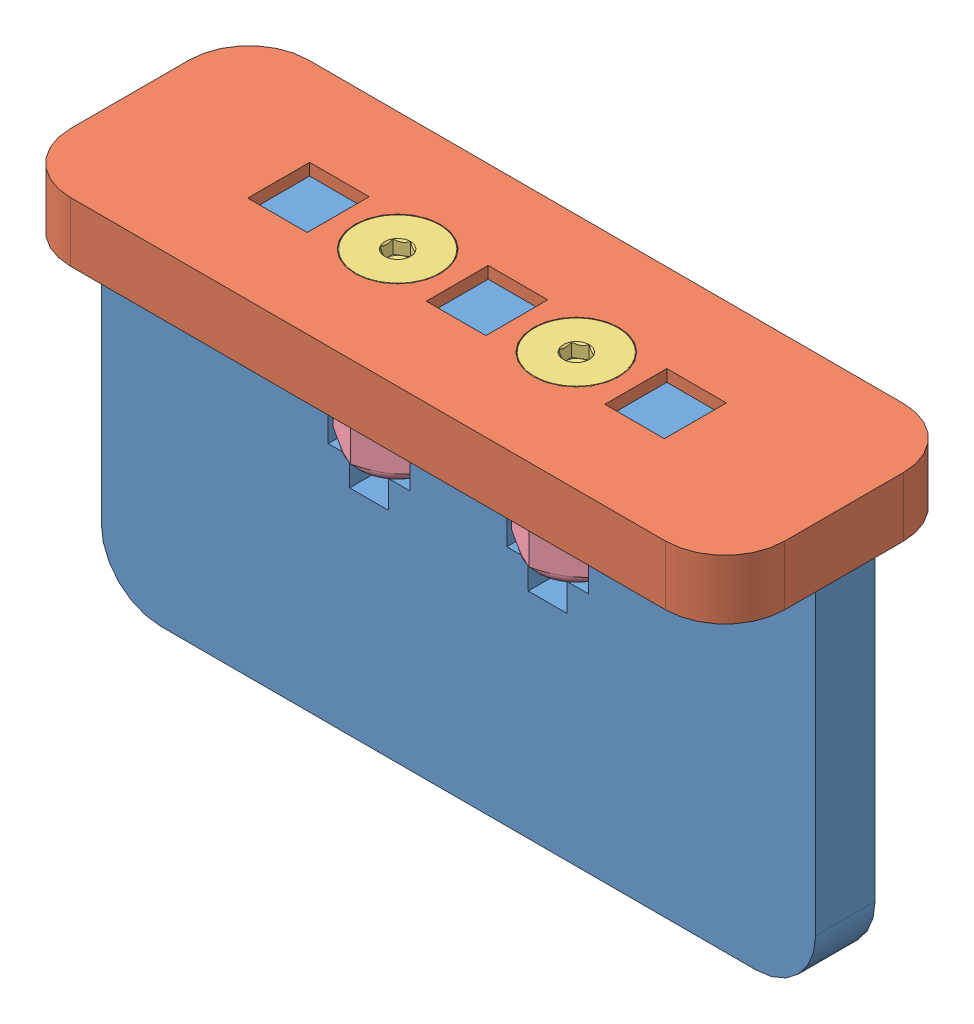
SolidWorks assembly FASTENER EXAMPLE EXPO, configuration Default. Lengths in mm.
Overall size (76.2 44.59 25.4).
6 component instances, 4 part files, 11 mates.
Components (placement in the parent):
- BOLT HOLE FOR EXPO-1: BOLT HOLE FOR EXPO [Default] at (54.6162 43.2156 -36.658) size (76.2 43.18 6.35)
- NUT HOLE FOR EXPO-1: NUT HOLE FOR EXPO [Default] at (54.6162 62.2656 -33.356) size (76.2 6.35 25.4)
- 92210A197-2: 92210A197 [Default] at (45.0912 65.7708 -33.356) x (1 0 0) z (0 1 0) size (9 9 19.19)
- 90631A009-1: 90631A009 [Default] at (45.0912 55.9156 -33.356) x (-1 0 0) z (0 0 1) size (8.73 6.1 10.08)
- 92210A197-3: 92210A197 [Default] at (64.1412 65.7708 -33.356) x (1 0 0) z (0 1 0) size (9 9 19.19)
- 90631A009-2: 90631A009 [Default] at (64.1412 55.9156 -33.356) x (-0.5 0 -0.866025) z (-0.866025 0 0.5) size (8.73 6.1 10.08)
Mates (geometry in assembly coordinates):
- Coincident1: coincident anti-aligned: plane of BOLT HOLE FOR EXPO-1 through (54.6162 43.2156 -36.658) normal (0 0 -1); plane of NUT HOLE FOR EXPO-1 through (70.4912 62.2656 -36.658) normal (0 0 1)
- Coincident2: coincident anti-aligned: plane of BOLT HOLE FOR EXPO-1 through (76.8412 67.3456 -36.658) normal (1 0 0); plane of NUT HOLE FOR EXPO-1 through (76.8412 62.2656 -36.658) normal (-1 0 0)
- Coincident3: coincident anti-aligned: plane of BOLT HOLE FOR EXPO-1 through (16.5162 62.2656 -30.308) normal (0 1 0); plane of NUT HOLE FOR EXPO-1 through (54.6162 62.2656 -33.356) normal (0 -1 0)
- Coincident7: coincident: cone of NUT HOLE FOR EXPO-1 through (45.0912 68.6156 -33.356) axis (0 -1 0); cone of 92210A197-2 through (45.0912 68.5315 -33.356) axis (0 -1 0)
- Coincident8: coincident: circle of 92210A197-2; cylinder of 90631A009-1 through (45.0912 50.8784 -33.356) axis (0 1 0) radius 1.7258
- Coincident9: coincident: plane of BOLT HOLE FOR EXPO-1 through (43.0084 55.9156 -36.6581) normal (0 -1 0); plane of 90631A009-1 through (45.0912 55.9156 -38.397) normal (0 1 0)
- Parallel1: parallel: plane of BOLT HOLE FOR EXPO-1 through (40.7224 55.9156 -36.6581) normal (1 0 0); plane of 90631A009-1 through (40.7255 49.9625 -30.8355) normal (-1 0 0)
- Coincident11: coincident: cone of NUT HOLE FOR EXPO-1 through (64.1412 68.6156 -33.356) axis (0 -1 0); cone of 92210A197-3 through (64.1412 68.5315 -33.356) axis (0 -1 0)
- Coincident12: coincident: circle of 92210A197-3; cylinder of 90631A009-2 through (64.1412 50.8784 -33.356) axis (0 1 0) radius 1.7258
- Coincident13: coincident: plane of BOLT HOLE FOR EXPO-1 through (68.51 55.9156 -36.6581) normal (0 -1 0); plane of 90631A009-2 through (68.5068 55.9156 -35.8765) normal (0 1 0)
- Parallel2: parallel: plane of BOLT HOLE FOR EXPO-1 through (59.7724 55.9156 -36.6581) normal (1 0 0); plane of 90631A009-2 through (68.5068 49.9625 -35.8765) normal (1 0 0)
